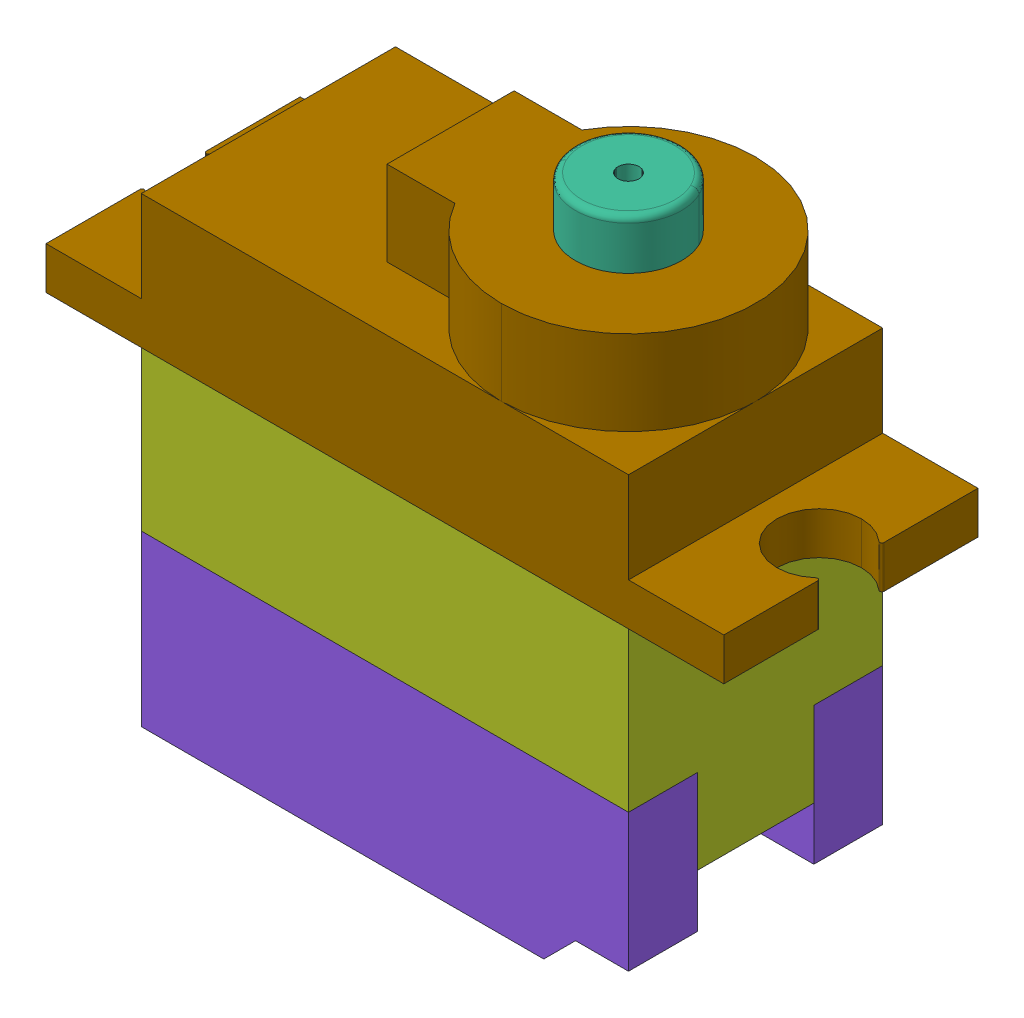
SolidWorks assembly ServoMotor.STEP, configuration Default. Lengths in mm.
Overall size (32 28.72 13.43).
25 component instances, 16 part files, 0 mates.
Components (placement in the parent):
- GearA.STEP-1: GearA.STEP [Default] at (6.407 21.1685 17.9874) x (0 1 0) z (-0.136177 0 0.990685) size (2 9.79 9.8)
  - spur gear_din_DIN - Spur gear 0.2M 47T 20PA 1FW ---S47A75H50L1N.STEP-1: spur gear_din_DIN - Spur gear 0.2M 47T 20PA 1FW ---S47A75H50L1N.STEP [Default] at (-2.8285 0.3328 0.7387) size (1 9.79 9.8)
  - spur gear_din_DIN - Spur gear 0.22M 11T 20PA 1FW ---S11A75H50L1N.STEP-1: spur gear_din_DIN - Spur gear 0.22M 11T 20PA 1FW ---S11A75H50L1N.STEP [Default] at (-0.8285 0.3328 0.7387) x (-1 0 0) z (0 -0.914108 -0.405471) size (1 2.81 2.84)
- GearA.STEP-2: GearA.STEP [Default] at (11.4399 22.3185 19.281) x (0 1 0) z (0.296142 0 -0.955144) size (2 9.79 9.8)
  - spur gear_din_DIN - Spur gear 0.2M 47T 20PA 1FW ---S47A75H50L1N.STEP-1: spur gear_din_DIN - Spur gear 0.2M 47T 20PA 1FW ---S47A75H50L1N.STEP [Default] at (-2.8285 0.3328 0.7387) size (1 9.79 9.8)
  - spur gear_din_DIN - Spur gear 0.22M 11T 20PA 1FW ---S11A75H50L1N.STEP-1: spur gear_din_DIN - Spur gear 0.22M 11T 20PA 1FW ---S11A75H50L1N.STEP [Default] at (-0.8285 0.3328 0.7387) x (-1 0 0) z (0 -0.914108 -0.405471) size (1 2.81 2.84)
- GearB.STEP-1: GearB.STEP [Default] at (5.6217 22.2511 18.2929) x (0 1 0) z (0.827248 0 0.561837) size (4 9.66 9.68)
  - spur gear_din_DIN - Spur gear 0.22M 42T 20PA 1FW ---S42A75H50L1N.STEP-1: spur gear_din_DIN - Spur gear 0.22M 42T 20PA 1FW ---S42A75H50L1N.STEP [Default] at (-1.6111 0.1158 0.5076) size (1 9.66 9.68)
  - spur gear_din_DIN - Spur gear 0.3M 10T 20PA 3FW ---S10A75H50L1N.STEP-1: spur gear_din_DIN - Spur gear 0.3M 10T 20PA 3FW ---S10A75H50L1N.STEP [Default] at (-0.6111 0.1158 0.5076) size (3 3.45 3.6)
- GearC.STEP-1: GearC.STEP [Default] at (14.6916 28.4136 18.6063) x (0 1 0) z (-0.903265 0 0.429082) size (9 8.96 8.96)
  - spur gear_din_DIN - Spur gear 0.3M 28T 20PA 4FW ---S28A75H50L1N.STEP-1: spur gear_din_DIN - Spur gear 0.3M 28T 20PA 4FW ---S28A75H50L1N.STEP [Default] at (-6.6235 1.1038 2.4814) size (4 8.96 8.96)
  - Part1^GearC.STEP-1: Part1^GearC.STEP [Default] at (-2.6235 1.1038 2.4814) x (0 0 -1) z (1 0 0) size (5 5 5)
- Servo Body.STEP-1: Servo Body.STEP [Default] at (6.4766 10.64 18.6739) size (23 11.5 12)
- Servo Bottom.STEP-1: Servo Bottom.STEP [Default] at (6.4766 2.64 18.6739) size (23 8 12)
- Servo Top.STEP-1: Servo Top.STEP [Default] at (6.4766 18.14 18.6739) size (32 10.3 12)
- Motor.STEP-1: Motor.STEP [Default] at (-6.9234 17.34 18.6739) x (1 0 0) z (0 -1 0) size (6 10.4 14)
- spur gear_din_DIN - Spur gear 0.25M 10T 20PA 1FW ---S10A75H50L0.5N.STEP-1: spur gear_din_DIN - Spur gear 0.25M 10T 20PA 1FW ---S10A75H50L0.5N.STEP [Default] at (-0.2234 19.34 18.6739) x (0 -1 0) z (0.796201 0 0.605033) size (1 2.87 3)
- Potmeter.STEP-1: Potmeter.STEP [Default] at (11.9766 14.14 18.6739) size (10 4 10)
- Electronics^ServoMotor.STEP-1: Electronics^ServoMotor.STEP [Default] at (6.4766 13.34 18.6739) x (-1 0 0) z (0 -1 0) size (11.3 10.4 2.4)
- Tengely^ServoMotor.STEP-1: Tengely^ServoMotor.STEP [Default] at (6.4766 17.34 18.6739) x (1 0 0) z (0 1 0) size (1 1 10)
- PotiTengely^ServoMotor.STEP-1: PotiTengely^ServoMotor.STEP [Default] at (11.9766 16.14 18.6739) x (1 0 0) z (0 1 0) size (1 1 13)
- cross recessed truss head screw_jis_JIS B 1111 Truss head screw M2 x 20 --8N.STEP-1: cross recessed truss head screw_jis_JIS B 1111 Truss head screw M2 x 20 --8N.STEP [Default] at (-3.5234 -8.559 23.1739) x (0 1 0) z (1 0 0) size (19.57 2.25 2.25)
- cross recessed truss head screw_jis_JIS B 1111 Truss head screw M2 x 20 --8N.STEP-2: cross recessed truss head screw_jis_JIS B 1111 Truss head screw M2 x 20 --8N.STEP [Default] at (-3.5234 -8.559 14.1739) x (0 1 0) z (1 0 0) size (19.57 2.25 2.25)
- cross recessed truss head screw_jis_JIS B 1111 Truss head screw M2 x 20 --8N.STEP-3: cross recessed truss head screw_jis_JIS B 1111 Truss head screw M2 x 20 --8N.STEP [Default] at (16.4766 -7.059 14.1739) x (0 1 0) z (1 0 0) size (19.57 2.25 2.25)
- cross recessed truss head screw_jis_JIS B 1111 Truss head screw M2 x 20 --8N.STEP-4: cross recessed truss head screw_jis_JIS B 1111 Truss head screw M2 x 20 --8N.STEP [Default] at (16.4766 -7.059 23.1739) x (0 1 0) z (1 0 0) size (19.57 2.25 2.25)
